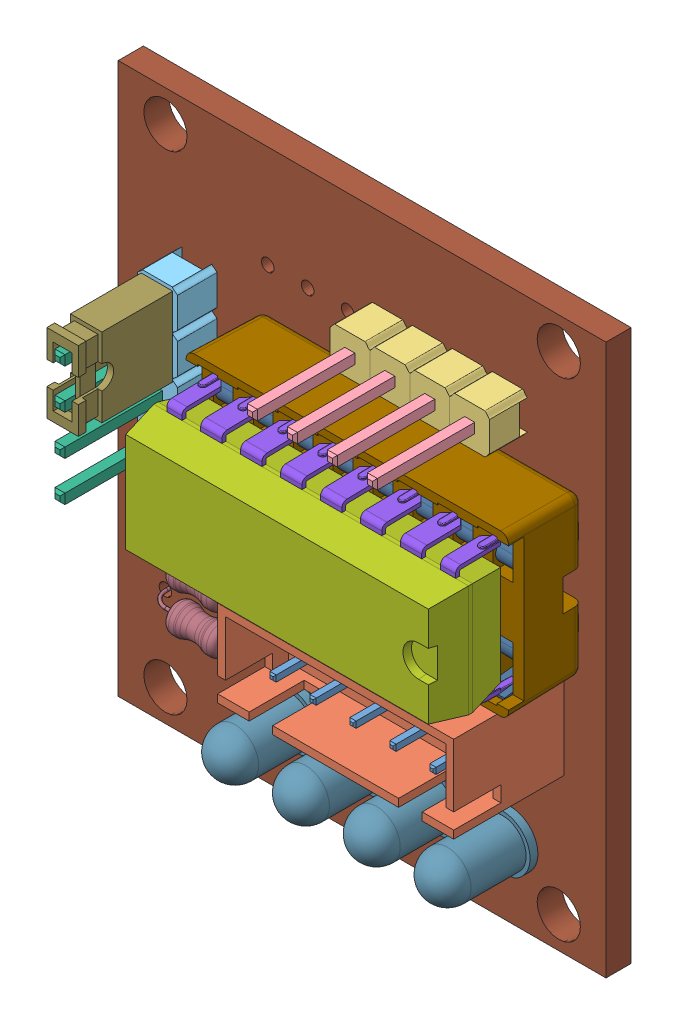
SolidWorks assembly ULN2003 Stepper Driver, configuration Default. Lengths in mm.
Overall size (31 35 12.67).
50 component instances, 14 part files, 0 mates.
Components (placement in the parent):
- ULN2003 Stepper Driver.stp-1: ULN2003 Stepper Driver.stp [Default] at origin size (31 35 12.67)
  - motor_connector.stp-1: motor_connector.stp [Default] at (-15.5 -17.5 0.2) size (15 5.5 9.89)
    - conn_lead.stp-1: conn_lead.stp [Default] at origin size (0.4 0.4 8.89)
    - conn_lead.stp-2: conn_lead.stp [Default] at (-2.54 0 0) size (0.4 0.4 8.89)
    - conn_lead.stp-3: conn_lead.stp [Default] at (-5.08 0 0) size (0.4 0.4 8.89)
    - conn_lead.stp-4: conn_lead.stp [Default] at (-7.62 0 0) size (0.4 0.4 8.89)
    - conn_lead.stp-5: conn_lead.stp [Default] at (-10.16 0 0) size (0.4 0.4 8.89)
    - motor_connector-0.stp-1: motor_connector-0.stp [Default] at origin size (15 5.5 7)
  - Pin Header 1x4 TH Pitch 2.54mm v2.stp-1: Pin Header 1x4 TH Pitch 2.54mm v2.stp [Default] at (1.6199 11.0001 1.46) size (10.16 2.54 11.43)
    - asm_pin.stp-1: asm_pin.stp [Default] at origin size (2.54 2.54 11.43)
      - spacer.stp-1: spacer.stp [Default] at origin size (2.54 2.54 2.54)
      - pin.stp-1: pin.stp [Default] at origin size (0.64 0.64 11.43)
    - asm_pin_1.stp-1: asm_pin_1.stp [Default] at (2.54 0 0) size (2.54 2.54 11.43)
      - spacer.stp-1: spacer.stp [Default] at origin size (2.54 2.54 2.54)
      - pin.stp-1: pin.stp [Default] at origin size (0.64 0.64 11.43)
    - asm_pin_2.stp-1: asm_pin_2.stp [Default] at (5.08 0 0) size (2.54 2.54 11.43)
      - spacer.stp-1: spacer.stp [Default] at origin size (2.54 2.54 2.54)
      - pin.stp-1: pin.stp [Default] at origin size (0.64 0.64 11.43)
    - asm_pin_3.stp-1: asm_pin_3.stp [Default] at (7.62 0 0) size (2.54 2.54 11.43)
      - spacer.stp-1: spacer.stp [Default] at origin size (2.54 2.54 2.54)
      - pin.stp-1: pin.stp [Default] at origin size (0.64 0.64 11.43)
  - Pin Header 1x4 TH Pitch 2.54mm v2 (1).stp-1: Pin Header 1x4 TH Pitch 2.54mm v2 (1).stp [Default] at (-10.4999 8.0001 1.5722) x (0 -1 0) z (0 0 1) size (10.16 2.54 11.43)
    - asm_pin (1).stp-1: asm_pin (1).stp [Default] at origin size (2.54 2.54 11.43)
      - spacer (1).stp-1: spacer (1).stp [Default] at origin size (2.54 2.54 2.54)
      - pin (1).stp-1: pin (1).stp [Default] at origin size (0.64 0.64 11.43)
    - asm_pin (1)_1.stp-1: asm_pin (1)_1.stp [Default] at (2.54 0 0) size (2.54 2.54 11.43)
      - spacer (1).stp-1: spacer (1).stp [Default] at origin size (2.54 2.54 2.54)
      - pin (1).stp-1: pin (1).stp [Default] at origin size (0.64 0.64 11.43)
    - asm_pin (1)_2.stp-1: asm_pin (1)_2.stp [Default] at (5.08 0 0) size (2.54 2.54 11.43)
      - spacer (1).stp-1: spacer (1).stp [Default] at origin size (2.54 2.54 2.54)
      - pin (1).stp-1: pin (1).stp [Default] at origin size (0.64 0.64 11.43)
    - asm_pin (1)_3.stp-1: asm_pin (1)_3.stp [Default] at (7.62 0 0) size (2.54 2.54 11.43)
      - spacer (1).stp-1: spacer (1).stp [Default] at origin size (2.54 2.54 2.54)
      - pin (1).stp-1: pin (1).stp [Default] at origin size (0.64 0.64 11.43)
  - dip16 v2.stp-1: dip16 v2.stp [Default] at (4.1 3.5 6) x (0 1 0) z (0 0 1) size (8.74 20 8.41)
    - package.stp-1: package.stp [Default] at origin size (7.1 20 4.6)
    - lead.stp-1: lead.stp [Default] at origin size (8.74 18.4 6.23)
  - dip16_socket v4.stp-1: dip16_socket v4.stp [Default] at (4.1 3.7 1.6) x (-1 0 0) z (0 0 1) size (20.49 10.21 8.2)
    - housing.stp-1: housing.stp [Default] at origin size (20.49 10.21 5.04)
    - pins.stp-1: pins.stp [Default] at origin size (19.03 9.24 7.72)
  - pcb.stp-1: pcb.stp [Default] at origin size (31 35 1.6)
  - jumper_connector.stp-1: jumper_connector.stp [Default] at (-15.35 -12.425 0) size (2 5 6)
  - r205.stp-1: r205.stp [Default] at (-15.3 -2.6 0) size (6.69 1.8 3.9)
  - r205.stp-2: r205.stp [Default] at (-15.3 -5.14 0) size (6.69 1.8 3.9)
  - r205.stp-3: r205.stp [Default] at (-15.3 -7.68 0) size (6.69 1.8 3.9)
  - r205.stp-4: r205.stp [Default] at (-15.3 -10.22 0) size (6.69 1.8 3.9)
  - LED 3mm.stp-1: LED 3mm.stp [Default] at (-3.9107 -12.6768 1.7661) x (0 -1 0) z (-1 0 0) size (3.33 7.5 3.5)
  - LED 3mm.stp-2: LED 3mm.stp [Default] at (0.5893 -12.6768 1.7661) x (0 -1 0) z (-1 0 0) size (3.33 7.5 3.5)
  - LED 3mm.stp-3: LED 3mm.stp [Default] at (5.0893 -12.6768 1.7661) x (0 -1 0) z (-1 0 0) size (3.33 7.5 3.5)
  - LED 3mm.stp-4: LED 3mm.stp [Default] at (9.5893 -12.6768 1.7661) x (0 -1 0) z (-1 0 0) size (3.33 7.5 3.5)
